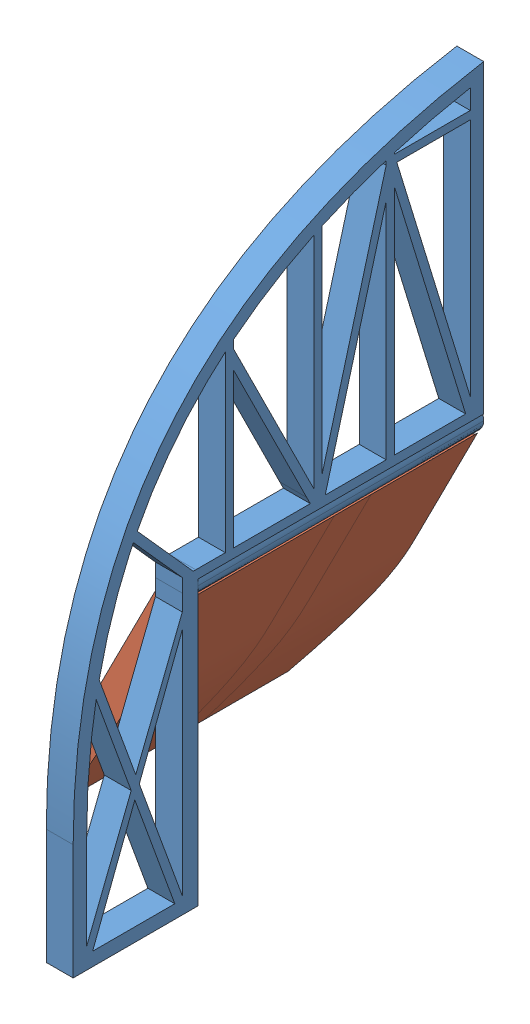
SolidWorks assembly Vertical_stabilizer, configuration Default. Lengths in mm.
Overall size (56.47 218.41 152.4).
3 component instances, 2 part files, 0 mates.
Components (placement in the parent):
- final VS VS.CATProduct-1: final VS VS.CATProduct [Default] at origin size (56.47 218.41 152.4)
  - new 1.CATPart-1: new 1.CATPart [Default] at (53.7668 21.8663 65.4843) size (9.98 218.41 152.4)
  - new 2.CATPart-1: new 2.CATPart [Default] at (55.1027 128.6983 119.6309) x (0.453006 0.891508 0) z (0 0 1) size (102.12 10 106.13)
